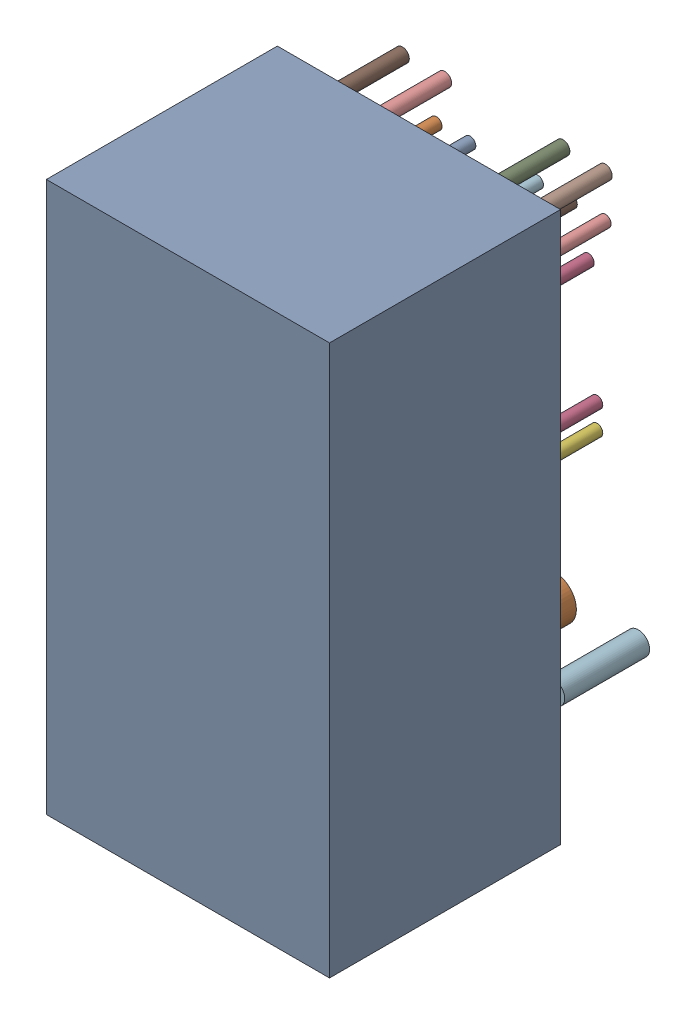
SolidWorks assembly RJ45.step, configuration Default. Lengths in mm.
Overall size (17.5 33.02 18.97).
4 component instances, 3 part files, 0 mates.
Components (placement in the parent):
- 6024909664.step-1: 6024909664.step [Default] at (38.539 23.881 0) x (1 0 0) z (0 0 1) size (17.5 33.02 18.97)
  - Body.step-1: Body.step [Default] at (0 0 0.1) size (17 33.02 13.87)
  - Lugs.step-1: Lugs.step [Default] at origin size (15.3 2.6 1.8)
  - Leads.step-1: Leads.step [Default] at origin size (17.5 24.59 5.1)
